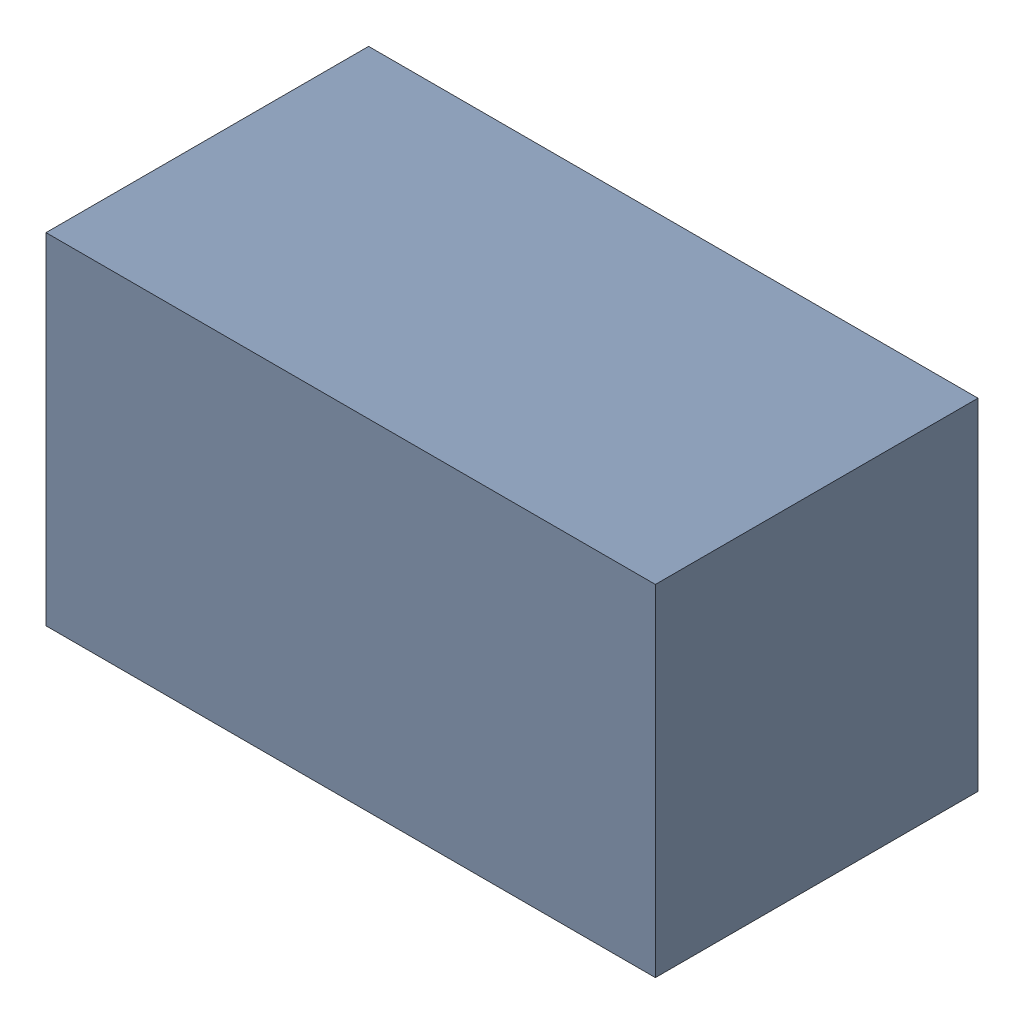
SolidWorks assembly R22, configuration Standard. Lengths in mm.
Overall size (1.7 0.95 0.9).
2 component instances, 1 part files, 0 mates.
Components (placement in the parent):
- 885541288-1: 885541288 [Standard] at (15.47 22.19 0) size (1.7 0.95 0.9)
  - Extruded_10-1: Extruded_10 [Standard] at origin size (1.7 0.95 0.9)
